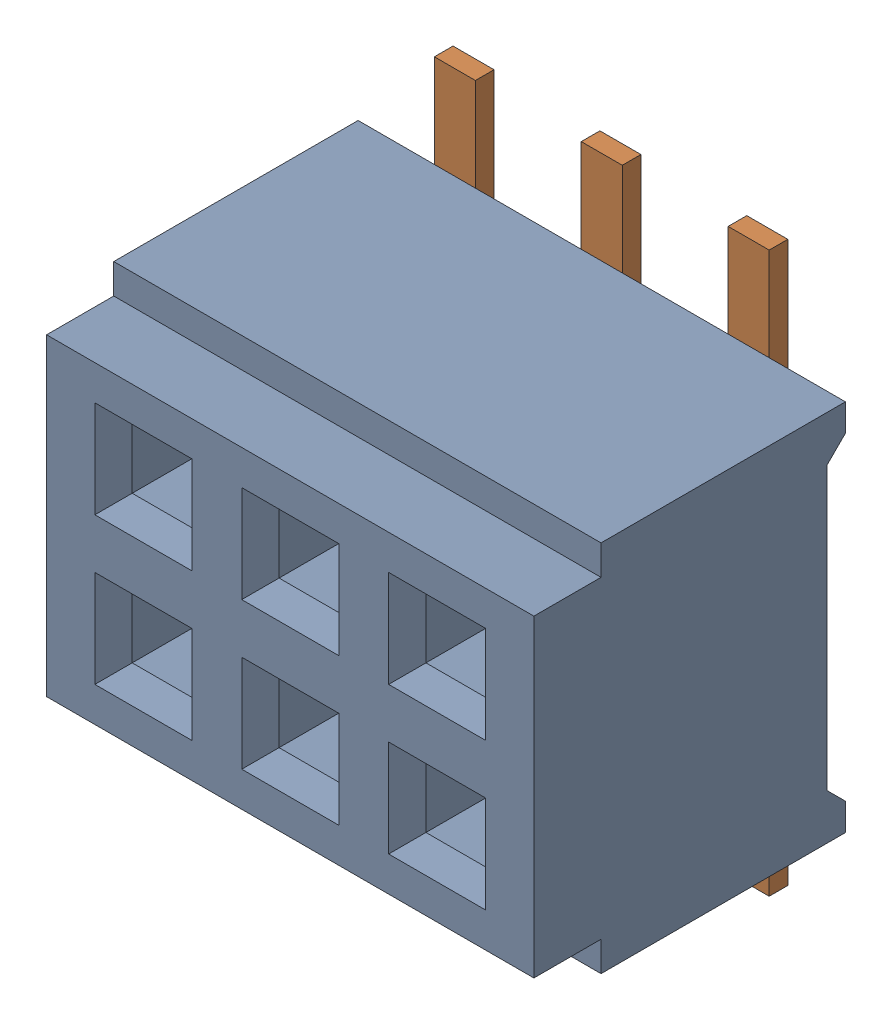
SolidWorks assembly J6, configuration ﾃﾞﾌｫﾙﾄ. Lengths in mm.
Overall size (3.32 3.81 2.25).
3 component instances, 2 part files, 0 mates.
Components (placement in the parent):
- CLM-103-02-F-D-1: CLM-103-02-F-D [ﾃﾞﾌｫﾙﾄ] at (40.7497 46.2499 0.1) x (1 0 0) z (0 -1 0) size (3.32 2.25 3.81)
  - _CLM-103-02-F-D_socket-1: _CLM-103-02-F-D_socket [ﾃﾞﾌｫﾙﾄ] at (-1.6587 0 0) size (3.32 2.12 2.54)
  - _C-03-02_pins-1: _C-03-02_pins [ﾃﾞﾌｫﾙﾄ] at origin size (2.99 1.14 3.81)
